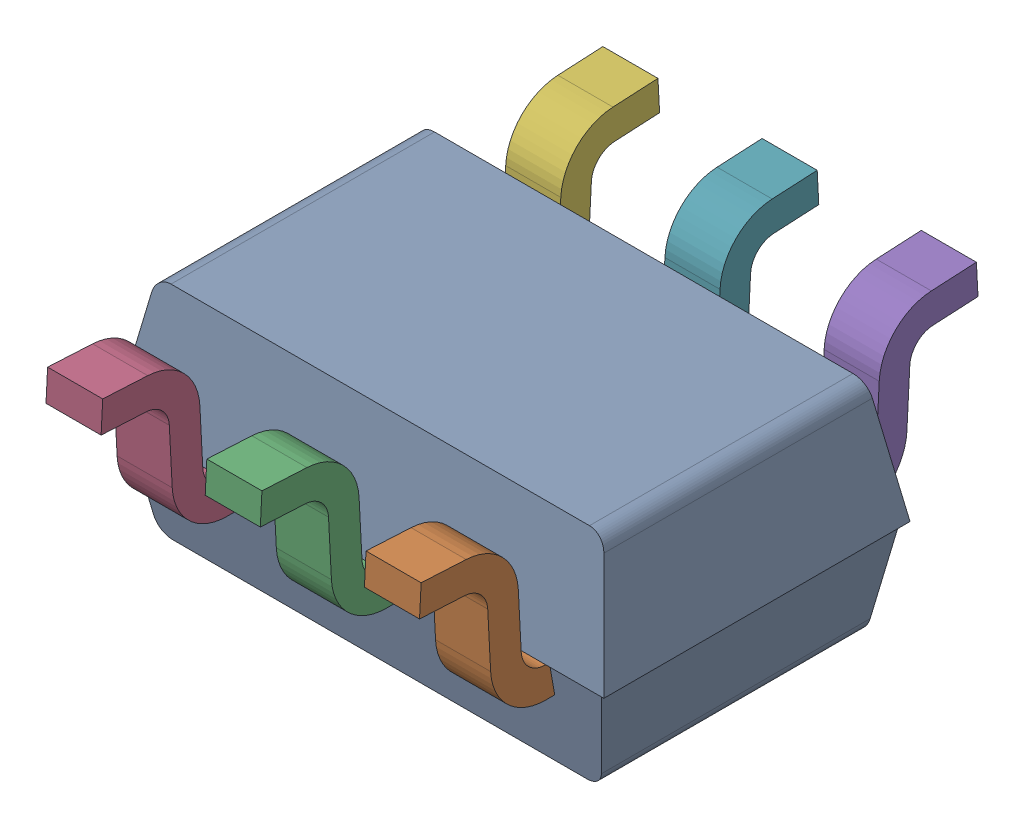
SolidWorks assembly DCK0006AakaMAA06, configuration Default. Lengths in mm.
Overall size (2 0.95 2.28).
8 component instances, 7 part files, 0 mates.
Components (placement in the parent):
- BODY_MAA06-1: BODY_MAA06 [Default] at origin size (2 0.9 1.25)
- LEADS_MAA06-1: LEADS_MAA06 [Default] at (0.65 0 0) x (0 0 1) z (1 0 0) size (2.28 0.67 1.53)
  - LEADS_MAA06_3-1: LEADS_MAA06_3 [Default] at origin size (0.55 0.67 0.23)
  - LEADS_MAA06_4-1: LEADS_MAA06_4 [Default] at origin size (0.55 0.67 0.23)
  - LEADS_MAA06_5-1: LEADS_MAA06_5 [Default] at origin size (0.55 0.67 0.23)
  - LEADS_MAA06_6-1: LEADS_MAA06_6 [Default] at origin size (0.55 0.67 0.23)
  - LEADS_MAA06_7-1: LEADS_MAA06_7 [Default] at origin size (0.55 0.67 0.23)
  - LEADS_MAA06_8-1: LEADS_MAA06_8 [Default] at origin size (0.55 0.67 0.23)
